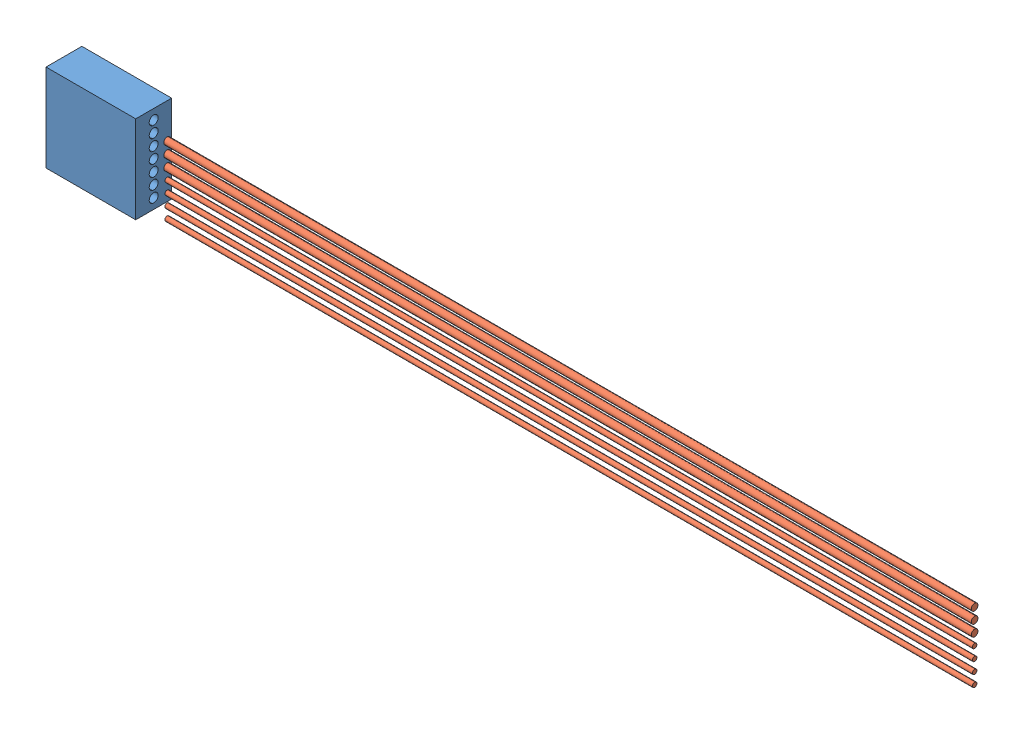
SolidWorks assembly Harness_29-CABLE_REALOP_ONE_ASSEMBLY, configuration AnnotateFlattenedRoute1 - Default. Lengths in mm.
Overall size (101.5 10.13 4).
3 component instances, 3 part files, 1 mates.
Components (placement in the parent):
- 7_PIN-1: 7_PIN [Default] at (-11.5 -7.625 2) x (0 -1 0) z (1 0 0) size (9.75 4 20)
- Cable^Harness_29-CABLE_REALOP_ONE_ASSEMBLY-1: Cable^Harness_29-CABLE_REALOP_ONE_ASSEMBLY [Default] at origin size (16.02 96.62 209.05) (suppressed, hidden, virtual)
- Flattened_Cable^Harness_29-CABLE_REALOP_ONE_ASSEMBLY-1: Flattened_Cable^Harness_29-CABLE_REALOP_ONE_ASSEMBLY [Default] at origin (virtual)
Mates (geometry in assembly coordinates):
- Coincident1041: coincident anti-aligned: plane of Z_FACE_SOLAR_ARRAY-2 through (16.9367 88.2518 126.3251) normal (0 0 1); plane of 7_PIN-1 through (56.3407 17.7518 126.3251) normal (0 0 -1)
